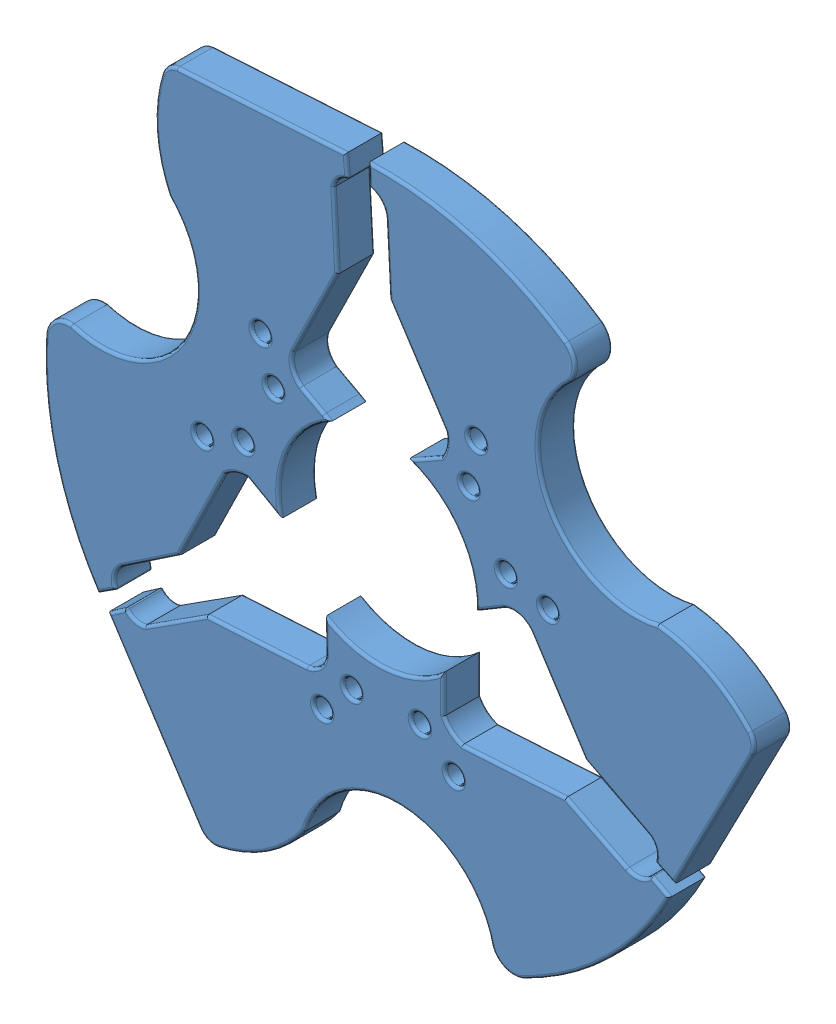
SolidWorks assembly starwheel morcego v1, configuration Valor predeterminado. Lengths in mm.
Overall size (306.53 268.91 13).
3 component instances, 1 part files, 6 mates.
Components (placement in the parent):
- Morcego 16Oz-1: Morcego 16Oz [Valor predeterminado] at (-80.7572 -56.483 192.4257) size (198.88 93.87 13)
- Morcego 16Oz-5: Morcego 16Oz [Valor predeterminado] at (-43.9669 218.4163 192.4257) x (-0.493556 -0.869714 0) z (0 0 1) size (198.88 93.87 13)
- Morcego 16Oz-6: Morcego 16Oz [Valor predeterminado] at (176.4846 47.1982 192.4257) x (-0.493556 0.869714 0) z (0 0 1) size (198.88 93.87 13)
Mates (geometry in assembly coordinates):
- Distância6: distance = 6.5 mm aligned: plane of Morcego 16Oz-5 through (-10.1293 163.3676 192.4257) normal (0 0 -1)
- Distância10: distance = 6.5 mm aligned: plane of Morcego 16Oz-6 through (111.8729 46.3777 192.4257) normal (0 0 -1)
- Coincidente28: coincident aligned: cylinder of Morcego 16Oz-5 through (17.6764 70.2549 205.4257) axis (0 0 -1) radius 35
- Coincidente32: coincident aligned: cylinder of Morcego 16Oz-6 through (17.6764 70.2549 205.4257) axis (0 0 -1) radius 35
- Distância14: distance = 22 mm: line of Morcego 16Oz-5 through (0.9707 101.0107 205.4257) axis (0 0 -1)
- Distância15: distance = 22 mm: line of Morcego 16Oz-6 through (28.6195 103.5002 205.4257) axis (0 0 -1)
